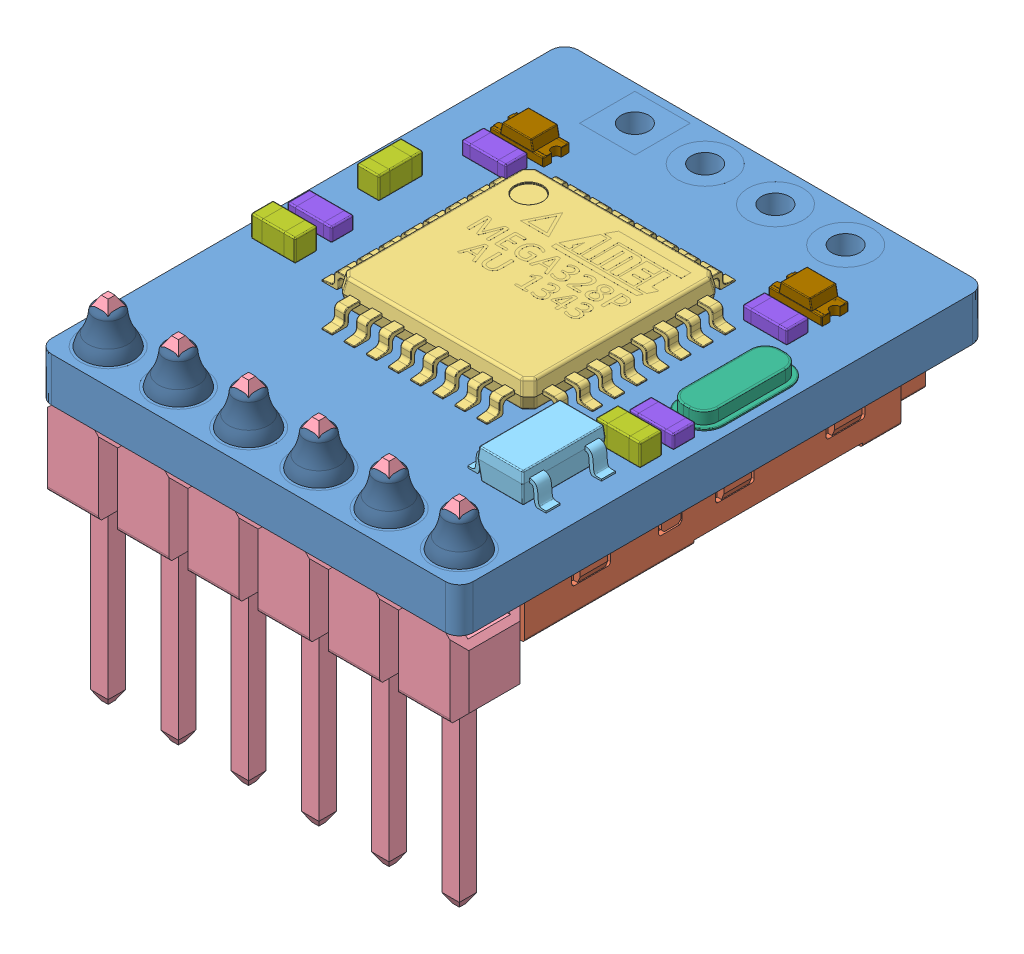
SolidWorks assembly OpenLog - pins down, configuration Default. Lengths in mm.
Overall size (15.24 12.7 19.05).
21 component instances, 10 part files, 45 mates.
Components (placement in the parent):
- OpenLog_PCB-1: OpenLog_PCB [Default] at origin size (15.24 1.6 19.05)
- microSDslot.stp-1: microSDslot.stp [Default] at (0.0152 -0.85 -1.0043) x (1 0 0) z (0 -1 0) size (14.1 15.2 1.88)
- ATmega-1: ATmega [Default] at (-0.0317 1.6 -0.6354) size (9 1.1 9)
- Pin Header 1x6 TH Pitch 2.54mm-1: Pin Header 1x6 TH Pitch 2.54mm [Default] at (-6.35 0.0014 8.255) x (1 0 0) z (0 -1 0) size (15.24 2.54 12.7)
- SOT23-5-1: SOT23-5 [Default] at (5.3808 1.495 4.313) x (-1 0 0) z (0 1 0) size (2.91 3.01 1.23)
- Fusion001-1: Fusion001 [Default] at (6.4694 1.6 -1.5764) x (0 0 -1) z (0 1 0) size (3.84 1.66 0.85)
- cap_603-1: cap_603 [Default] at (7.1016 2.4 2.4707) x (-1 0 0) z (0 0 1) size (1.6 0.8 0.8)
- res_603-1: res_603 [Default] at (7.1399 2.1 1.3029) x (-1 0 0) z (0 0 1) size (1.6 0.5 0.8)
- cap_603-2: cap_603 [Default] at (-7.1409 1.6 2.3005) size (1.6 0.8 0.8)
- res_603-2: res_603 [Default] at (-5.9255 1.6 -4.0991) size (1.6 0.5 0.8)
- res_603-3: res_603 [Default] at (4.3139 1.6 -4.0229) size (1.6 0.5 0.8)
- res_603-4: res_603 [Default] at (-5.5292 2.1 0.9961) x (-1 0 0) z (0 0 1) size (1.6 0.5 0.8)
- Surface Mount Chip LED 3.2x1.6mm-1: Surface Mount Chip LED 3.2x1.6mm [Default] at (4.0264 1.606 -5.2554) x (1 0 0) z (0 1 0) size (1.92 0.96 0.72)
- Surface Mount Chip LED 3.2x1.6mm-2: Surface Mount Chip LED 3.2x1.6mm [Default] at (-4.0759 1.606 -6.1626) x (-1 0 0) z (0 1 0) size (1.92 0.96 0.72)
- cap_603-3: cap_603 [Default] at (-6.7814 2.4 -1.167) x (0 0 -1) z (-1 0 0) size (1.6 0.8 0.8)
- solder-5: solder [Default] at (-6.35 1.6 8.255) size (1.8 1.3 1.8)
- solder-7: solder [Default] at (-3.81 1.6 8.255) size (1.8 1.3 1.8)
- solder-8: solder [Default] at (-1.27 1.6 8.255) size (1.8 1.3 1.8)
- solder-9: solder [Default] at (1.27 1.6 8.255) size (1.8 1.3 1.8)
- solder-10: solder [Default] at (3.81 1.6 8.255) size (1.8 1.3 1.8)
- solder-11: solder [Default] at (6.35 1.6 8.255) size (1.8 1.3 1.8)
Mates (geometry in assembly coordinates):
- Coincident1: coincident aligned: plane of OpenLog_PCB-1 through (0 0 0) normal (0 0 1)
- Coincident3: coincident aligned: plane of OpenLog_PCB-1 through (0 0 0) normal (1 0 0)
- Coincident4: coincident aligned: plane of OpenLog_PCB-1 through (0 0 0) normal (0 1 0)
- Coincident8: coincident anti-aligned: plane of OpenLog_PCB-1 through (0 0 0) normal (0 -1 0); plane of microSDslot.stp-1 through (0.0152 0 -1.0043) normal (0 1 0)
- Coincident9: coincident anti-aligned: plane of OpenLog_PCB-1 through (0 1.6 0) normal (0 1 0); plane of ATmega-1 through (-0.0317 1.6 -0.6354) normal (0 -1 0)
- Coincident11: coincident anti-aligned: plane of OpenLog_PCB-1 through (0 1.6 0) normal (0 1 0); plane of SOT23-5-1 through (4.6183 1.6 2.813) normal (0 -1 0)
- Parallel3: parallel anti-aligned: line of SOT23-5-1 through (4.5557 2.3233 2.8628) axis (0 0 1); line of OpenLog_PCB-1 through (7.62 1.6 9.025) axis (0 0 -1)
- Coincident13: coincident anti-aligned: plane of OpenLog_PCB-1 through (0 1.6 0) normal (0 1 0); plane of Fusion001-1 through (5.6557 1.6 0.3311) normal (0 -1 0)
- Parallel4: parallel anti-aligned: plane of OpenLog_PCB-1 through (7.62 1.6 -9.525) normal (1 0 0); plane of Fusion001-1 through (5.8394 1.66 0.1649) normal (-1 0 0)
- Coincident15: coincident anti-aligned: plane of OpenLog_PCB-1 through (0 1.6 0) normal (0 1 0); plane of cap_603-1 through (7.1016 1.6 2.4707) normal (0 -1 0)
- Parallel5: parallel aligned: plane of OpenLog_PCB-1 through (-7.62 1.6 -9.525) normal (-1 0 0); plane of cap_603-1 through (5.5016 1.6 1.6707) normal (-1 0 0)
- Coincident17: coincident anti-aligned: plane of OpenLog_PCB-1 through (0 1.6 0) normal (0 1 0); plane of res_603-1 through (7.1399 1.6 1.3029) normal (0 -1 0)
- Parallel6: parallel aligned: plane of OpenLog_PCB-1 through (-7.62 1.6 -9.525) normal (-1 0 0); plane of res_603-1 through (5.5399 1.6 0.5029) normal (-1 0 0)
- Coincident191: coincident anti-aligned: plane of OpenLog_PCB-1 through (0 1.6 0) normal (0 1 0); plane of cap_603-2 through (-7.1409 1.6 2.3005) normal (0 -1 0)
- Coincident201: coincident anti-aligned: plane of OpenLog_PCB-1 through (0 1.6 0) normal (0 1 0); plane of res_603-2 through (-5.9255 1.6 -4.0991) normal (0 -1 0)
- Parallel7: parallel aligned: plane of OpenLog_PCB-1 through (-7.62 1.6 -9.525) normal (-1 0 0); plane of res_603-2 through (-5.9255 2.1 -4.0991) normal (-1 0 0)
- Parallel8: parallel aligned: plane of OpenLog_PCB-1 through (-7.62 1.6 -9.525) normal (-1 0 0); plane of cap_603-2 through (-7.1409 2.4 2.3005) normal (-1 0 0)
- Lock1: lock: unknown of OpenLog_PCB-1; unknown of ATmega-1
- Coincident261: coincident anti-aligned: plane of OpenLog_PCB-1 through (0 1.6 0) normal (0 1 0); plane of res_603-4 through (-5.5292 1.6 0.9961) normal (0 -1 0)
- Parallel10: parallel aligned: plane of OpenLog_PCB-1 through (-7.62 1.6 -9.525) normal (-1 0 0); plane of res_603-4 through (-7.1292 1.6 0.1961) normal (-1 0 0)
- Coincident28: coincident anti-aligned: plane of OpenLog_PCB-1 through (0 1.6 0) normal (0 1 0); plane of Surface Mount Chip LED 3.2x1.6mm-1 through (4.8664 1.6 -6.2154) normal (0 -1 0)
- Parallel12: parallel aligned: plane of OpenLog_PCB-1 through (-7.62 1.6 -9.525) normal (-1 0 0); plane of Surface Mount Chip LED 3.2x1.6mm-2 through (-5.9959 1.606 -6.1626) normal (-1 0 0)
- Coincident31: coincident anti-aligned: plane of OpenLog_PCB-1 through (0 1.6 0) normal (0 1 0); plane of Surface Mount Chip LED 3.2x1.6mm-2 through (-4.9159 1.6 -5.2026) normal (0 -1 0)
- Coincident321: coincident anti-aligned: plane of OpenLog_PCB-1 through (0 1.6 0) normal (0 1 0); plane of cap_603-3 through (-6.7814 1.6 -1.167) normal (0 -1 0)
- Parallel13: parallel aligned: plane of OpenLog_PCB-1 through (-7.62 1.6 -9.525) normal (0 0 -1); plane of cap_603-3 through (-5.9814 1.6 -2.767) normal (0 0 -1)
- Lock9: lock: unknown of OpenLog_PCB-1; unknown of cap_603-2
- Lock10: lock: unknown of OpenLog_PCB-1; unknown of res_603-4
- Lock11: lock: unknown of OpenLog_PCB-1; unknown of cap_603-3
- Lock12: lock: unknown of OpenLog_PCB-1; unknown of res_603-2
- Lock13: lock: unknown of OpenLog_PCB-1; unknown of Surface Mount Chip LED 3.2x1.6mm-2
- Lock14: lock: unknown of OpenLog_PCB-1; unknown of Surface Mount Chip LED 3.2x1.6mm-1
- Parallel17: parallel anti-aligned: plane of OpenLog_PCB-1 through (0 1.6 0) normal (0 1 0); plane of res_603-3 through (4.3139 1.6 -4.0229) normal (0 -1 0)
- Coincident47: coincident anti-aligned: plane of OpenLog_PCB-1 through (0 1.6 0) normal (0 1 0); plane of res_603-3 through (4.3139 1.6 -4.0229) normal (0 -1 0)
- Lock15: lock: unknown of OpenLog_PCB-1; unknown of res_603-3
- Lock16: lock: unknown of OpenLog_PCB-1; unknown of Fusion001-1
- Lock17: lock: unknown of OpenLog_PCB-1; unknown of res_603-1
- Lock18: lock: unknown of OpenLog_PCB-1; unknown of cap_603-1
- Lock19: lock: unknown of OpenLog_PCB-1; unknown of SOT23-5-1
- Lock21: lock: unknown of OpenLog_PCB-1; unknown of microSDslot.stp-1
- Coincident322: coincident anti-aligned: plane of OpenLog_PCB-1 through (0 0 0) normal (0 -1 0); plane of Pin Header 1x6 TH Pitch 2.54mm-1 through (5.553 0 6.975) normal (0 1 0)
- Coincident323: coincident aligned: plane of OpenLog_PCB-1 through (7.62 1.6 -9.525) normal (1 0 0); plane of Pin Header 1x6 TH Pitch 2.54mm-1 through (7.62 -2.4727 7.312) normal (1 0 0)
- Coincident324: coincident aligned: plane of OpenLog_PCB-1 through (-7.62 1.6 9.525) normal (0 0 1); plane of Pin Header 1x6 TH Pitch 2.54mm-1 through (5.407 0.028 9.525) normal (0 0 1)
- Coincident325: coincident anti-aligned: plane of OpenLog_PCB-1 through (0 1.6 0) normal (0 1 0); plane of solder-5 through (-6.35 1.6 8.255) normal (0 -1 0)
- Concentric1: concentric anti-aligned: circle of OpenLog_PCB-1; circle of solder-5
- Parallel18: parallel anti-aligned: plane of OpenLog_PCB-1 through (-7.62 1.6 -9.525) normal (-1 0 0); plane of solder-5 through (-6.35 1.6 8.255) normal (1 0 0)
